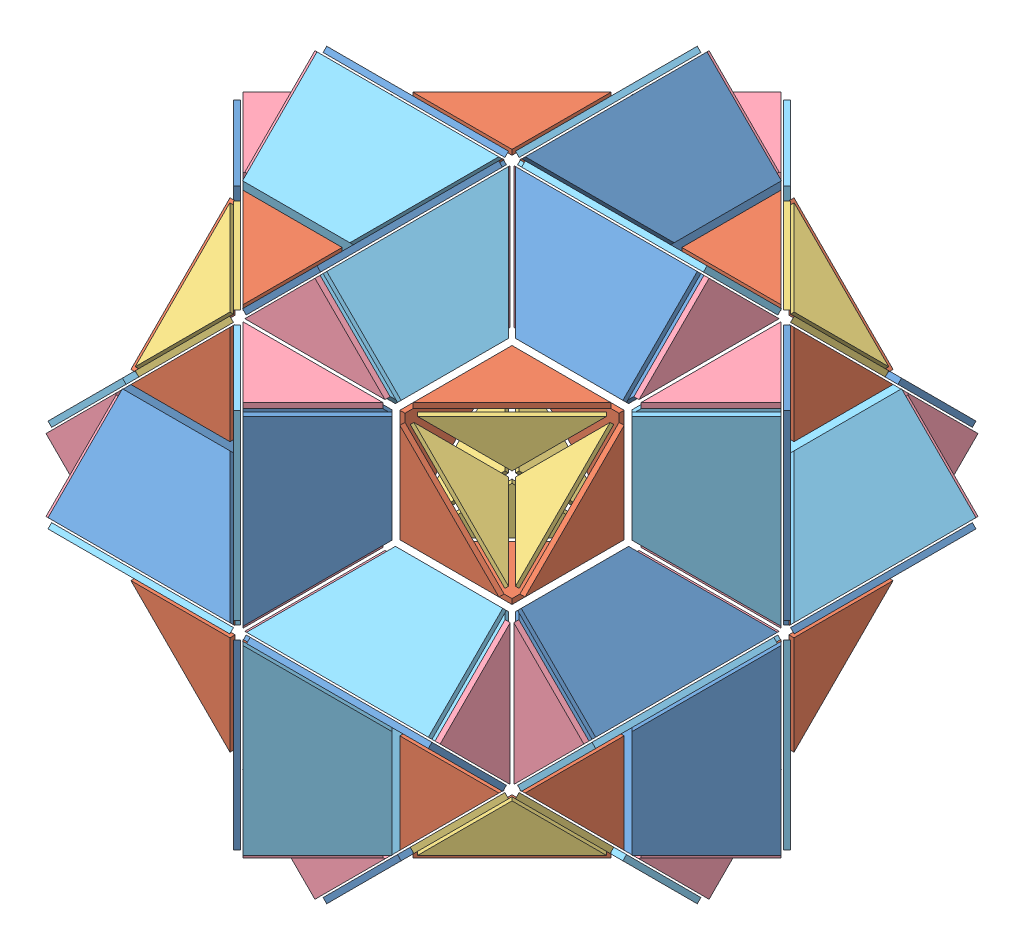
SolidWorks assembly Full Fucker, configuration Default. Lengths in mm.
Overall size (320.14 320.14 320.14).
318 component instances, 12 part files, 6 mates.
Components (placement in the parent):
- Face-1: Face [Default] at origin size (230.41 76.56 230.41)
  - Face Quarter-1: Face Quarter [Default] at origin size (152.13 76.56 114.47)
    - Goux Like-1: Goux Like [Default] at origin (suppressed, hidden)
    - trapezoid-1: trapezoid [Default] at origin size (45.63 45.63 106.26)
    - triangle 1-1: triangle 1 [Default] at origin size (57.93 3 57.93)
    - triangle 2-1: triangle 2 [Default] at origin size (57.43 27.65 57.43)
    - triangle 3-1: triangle 3 [Default] at origin size (81.93 40.97 3)
    - triangle 4-1: triangle 4 [Default] at origin size (106.26 45.63 45.63)
    - Joiner_1-1: Joiner_1 [Default] at (80.4015 -113.7049 80.4015) x (0 -1 0) z (-0.707107 0 0.707107) (suppressed, hidden)
    - Joiner_2-1: Joiner_2 [Default] at (0 -160.803 0) x (-0.707107 -0.707107 0) z (0 0 1) (suppressed, hidden)
    - Joiner_3-1: Joiner_3 [Default] at (80.4015 -80.4015 113.7049) x (0.707107 -0.707107 0) z (-0.707107 -0.707107 0) (suppressed, hidden)
    - Joiner_Open - 1-2: Joiner_Open - 1 [Default] at (0 -113.7049 113.7049) x (0 1 0) z (1 0 0) (suppressed, hidden)
    - Joiner_Open - 2-1: Joiner_Open - 2 [Default] at (47.0981 -113.7049 0) x (-1 0 0) z (0 0 1) (suppressed, hidden)
    - Joiner_Open - 3-1: Joiner_Open - 3 [Default] at (53.601 -107.202 53.601) x (-0.816497 0.408248 0.408248) z (0.57735 0.57735 0.57735) (suppressed, hidden)
  - Face Quarter-2: Face Quarter [Default] x (0 0 -1) z (1 0 0) size (152.13 76.56 114.47)
    - Goux Like-1: Goux Like [Default] at origin (suppressed, hidden)
    - trapezoid-1: trapezoid [Default] at origin size (45.63 45.63 106.26)
    - triangle 1-1: triangle 1 [Default] at origin size (57.93 3 57.93)
    - triangle 2-1: triangle 2 [Default] at origin size (57.43 27.65 57.43)
    - triangle 3-1: triangle 3 [Default] at origin size (81.93 40.97 3)
    - triangle 4-1: triangle 4 [Default] at origin size (106.26 45.63 45.63)
    - Joiner_1-1: Joiner_1 [Default] at (80.4015 -113.7049 80.4015) x (0 -1 0) z (-0.707107 0 0.707107) (suppressed, hidden)
    - Joiner_2-1: Joiner_2 [Default] at (0 -160.803 0) x (-0.707107 -0.707107 0) z (0 0 1) (suppressed, hidden)
    - Joiner_3-1: Joiner_3 [Default] at (80.4015 -80.4015 113.7049) x (0.707107 -0.707107 0) z (-0.707107 -0.707107 0) (suppressed, hidden)
    - Joiner_Open - 1-2: Joiner_Open - 1 [Default] at (0 -113.7049 113.7049) x (0 1 0) z (1 0 0) (suppressed, hidden)
    - Joiner_Open - 2-1: Joiner_Open - 2 [Default] at (47.0981 -113.7049 0) x (-1 0 0) z (0 0 1) (suppressed, hidden)
    - Joiner_Open - 3-1: Joiner_Open - 3 [Default] at (53.601 -107.202 53.601) x (-0.816497 0.408248 0.408248) z (0.57735 0.57735 0.57735) (suppressed, hidden)
  - Face Quarter-3: Face Quarter [Default] x (-1 0 0) z (0 0 -1) size (152.13 76.56 114.47)
    - Goux Like-1: Goux Like [Default] at origin (suppressed, hidden)
    - trapezoid-1: trapezoid [Default] at origin size (45.63 45.63 106.26)
    - triangle 1-1: triangle 1 [Default] at origin size (57.93 3 57.93)
    - triangle 2-1: triangle 2 [Default] at origin size (57.43 27.65 57.43)
    - triangle 3-1: triangle 3 [Default] at origin size (81.93 40.97 3)
    - triangle 4-1: triangle 4 [Default] at origin size (106.26 45.63 45.63)
    - Joiner_1-1: Joiner_1 [Default] at (80.4015 -113.7049 80.4015) x (0 -1 0) z (-0.707107 0 0.707107) (suppressed, hidden)
    - Joiner_2-1: Joiner_2 [Default] at (0 -160.803 0) x (-0.707107 -0.707107 0) z (0 0 1) (suppressed, hidden)
    - Joiner_3-1: Joiner_3 [Default] at (80.4015 -80.4015 113.7049) x (0.707107 -0.707107 0) z (-0.707107 -0.707107 0) (suppressed, hidden)
    - Joiner_Open - 1-2: Joiner_Open - 1 [Default] at (0 -113.7049 113.7049) x (0 1 0) z (1 0 0) (suppressed, hidden)
    - Joiner_Open - 2-1: Joiner_Open - 2 [Default] at (47.0981 -113.7049 0) x (-1 0 0) z (0 0 1) (suppressed, hidden)
    - Joiner_Open - 3-1: Joiner_Open - 3 [Default] at (53.601 -107.202 53.601) x (-0.816497 0.408248 0.408248) z (0.57735 0.57735 0.57735) (suppressed, hidden)
  - Face Quarter-4: Face Quarter [Default] x (0 0 1) z (-1 0 0) size (152.13 76.56 114.47)
    - Goux Like-1: Goux Like [Default] at origin (suppressed, hidden)
    - trapezoid-1: trapezoid [Default] at origin size (45.63 45.63 106.26)
    - triangle 1-1: triangle 1 [Default] at origin size (57.93 3 57.93)
    - triangle 2-1: triangle 2 [Default] at origin size (57.43 27.65 57.43)
    - triangle 3-1: triangle 3 [Default] at origin size (81.93 40.97 3)
    - triangle 4-1: triangle 4 [Default] at origin size (106.26 45.63 45.63)
    - Joiner_1-1: Joiner_1 [Default] at (80.4015 -113.7049 80.4015) x (0 -1 0) z (-0.707107 0 0.707107) (suppressed, hidden)
    - Joiner_2-1: Joiner_2 [Default] at (0 -160.803 0) x (-0.707107 -0.707107 0) z (0 0 1) (suppressed, hidden)
    - Joiner_3-1: Joiner_3 [Default] at (80.4015 -80.4015 113.7049) x (0.707107 -0.707107 0) z (-0.707107 -0.707107 0) (suppressed, hidden)
    - Joiner_Open - 1-2: Joiner_Open - 1 [Default] at (0 -113.7049 113.7049) x (0 1 0) z (1 0 0) (suppressed, hidden)
    - Joiner_Open - 2-1: Joiner_Open - 2 [Default] at (47.0981 -113.7049 0) x (-1 0 0) z (0 0 1) (suppressed, hidden)
    - Joiner_Open - 3-1: Joiner_Open - 3 [Default] at (53.601 -107.202 53.601) x (-0.816497 0.408248 0.408248) z (0.57735 0.57735 0.57735) (suppressed, hidden)
- Face-2: Face [Default] x (1 0 0) z (0 0 -1) size (230.41 76.56 230.41)
  - Face Quarter-1: Face Quarter [Default] at origin size (152.13 76.56 114.47)
    - Goux Like-1: Goux Like [Default] at origin (suppressed, hidden)
    - trapezoid-1: trapezoid [Default] at origin size (45.63 45.63 106.26)
    - triangle 1-1: triangle 1 [Default] at origin size (57.93 3 57.93)
    - triangle 2-1: triangle 2 [Default] at origin size (57.43 27.65 57.43)
    - triangle 3-1: triangle 3 [Default] at origin size (81.93 40.97 3)
    - triangle 4-1: triangle 4 [Default] at origin size (106.26 45.63 45.63)
    - Joiner_1-1: Joiner_1 [Default] at (80.4015 -113.7049 80.4015) x (0 -1 0) z (-0.707107 0 0.707107) (suppressed, hidden)
    - Joiner_2-1: Joiner_2 [Default] at (0 -160.803 0) x (-0.707107 -0.707107 0) z (0 0 1) (suppressed, hidden)
    - Joiner_3-1: Joiner_3 [Default] at (80.4015 -80.4015 113.7049) x (0.707107 -0.707107 0) z (-0.707107 -0.707107 0) (suppressed, hidden)
    - Joiner_Open - 1-2: Joiner_Open - 1 [Default] at (0 -113.7049 113.7049) x (0 1 0) z (1 0 0) (suppressed, hidden)
    - Joiner_Open - 2-1: Joiner_Open - 2 [Default] at (47.0981 -113.7049 0) x (-1 0 0) z (0 0 1) (suppressed, hidden)
    - Joiner_Open - 3-1: Joiner_Open - 3 [Default] at (53.601 -107.202 53.601) x (-0.816497 0.408248 0.408248) z (0.57735 0.57735 0.57735) (suppressed, hidden)
  - Face Quarter-2: Face Quarter [Default] x (0 0 -1) z (1 0 0) size (152.13 76.56 114.47)
    - Goux Like-1: Goux Like [Default] at origin (suppressed, hidden)
    - trapezoid-1: trapezoid [Default] at origin size (45.63 45.63 106.26)
    - triangle 1-1: triangle 1 [Default] at origin size (57.93 3 57.93)
    - triangle 2-1: triangle 2 [Default] at origin size (57.43 27.65 57.43)
    - triangle 3-1: triangle 3 [Default] at origin size (81.93 40.97 3)
    - triangle 4-1: triangle 4 [Default] at origin size (106.26 45.63 45.63)
    - Joiner_1-1: Joiner_1 [Default] at (80.4015 -113.7049 80.4015) x (0 -1 0) z (-0.707107 0 0.707107) (suppressed, hidden)
    - Joiner_2-1: Joiner_2 [Default] at (0 -160.803 0) x (-0.707107 -0.707107 0) z (0 0 1) (suppressed, hidden)
    - Joiner_3-1: Joiner_3 [Default] at (80.4015 -80.4015 113.7049) x (0.707107 -0.707107 0) z (-0.707107 -0.707107 0) (suppressed, hidden)
    - Joiner_Open - 1-2: Joiner_Open - 1 [Default] at (0 -113.7049 113.7049) x (0 1 0) z (1 0 0) (suppressed, hidden)
    - Joiner_Open - 2-1: Joiner_Open - 2 [Default] at (47.0981 -113.7049 0) x (-1 0 0) z (0 0 1) (suppressed, hidden)
    - Joiner_Open - 3-1: Joiner_Open - 3 [Default] at (53.601 -107.202 53.601) x (-0.816497 0.408248 0.408248) z (0.57735 0.57735 0.57735) (suppressed, hidden)
  - Face Quarter-3: Face Quarter [Default] x (-1 0 0) z (0 0 -1) size (152.13 76.56 114.47)
    - Goux Like-1: Goux Like [Default] at origin (suppressed, hidden)
    - trapezoid-1: trapezoid [Default] at origin size (45.63 45.63 106.26)
    - triangle 1-1: triangle 1 [Default] at origin size (57.93 3 57.93)
    - triangle 2-1: triangle 2 [Default] at origin size (57.43 27.65 57.43)
    - triangle 3-1: triangle 3 [Default] at origin size (81.93 40.97 3)
    - triangle 4-1: triangle 4 [Default] at origin size (106.26 45.63 45.63)
    - Joiner_1-1: Joiner_1 [Default] at (80.4015 -113.7049 80.4015) x (0 -1 0) z (-0.707107 0 0.707107) (suppressed, hidden)
    - Joiner_2-1: Joiner_2 [Default] at (0 -160.803 0) x (-0.707107 -0.707107 0) z (0 0 1) (suppressed, hidden)
    - Joiner_3-1: Joiner_3 [Default] at (80.4015 -80.4015 113.7049) x (0.707107 -0.707107 0) z (-0.707107 -0.707107 0) (suppressed, hidden)
    - Joiner_Open - 1-2: Joiner_Open - 1 [Default] at (0 -113.7049 113.7049) x (0 1 0) z (1 0 0) (suppressed, hidden)
    - Joiner_Open - 2-1: Joiner_Open - 2 [Default] at (47.0981 -113.7049 0) x (-1 0 0) z (0 0 1) (suppressed, hidden)
    - Joiner_Open - 3-1: Joiner_Open - 3 [Default] at (53.601 -107.202 53.601) x (-0.816497 0.408248 0.408248) z (0.57735 0.57735 0.57735) (suppressed, hidden)
  - Face Quarter-4: Face Quarter [Default] x (0 0 1) z (-1 0 0) size (152.13 76.56 114.47)
    - Goux Like-1: Goux Like [Default] at origin (suppressed, hidden)
    - trapezoid-1: trapezoid [Default] at origin size (45.63 45.63 106.26)
    - triangle 1-1: triangle 1 [Default] at origin size (57.93 3 57.93)
    - triangle 2-1: triangle 2 [Default] at origin size (57.43 27.65 57.43)
    - triangle 3-1: triangle 3 [Default] at origin size (81.93 40.97 3)
    - triangle 4-1: triangle 4 [Default] at origin size (106.26 45.63 45.63)
    - Joiner_1-1: Joiner_1 [Default] at (80.4015 -113.7049 80.4015) x (0 -1 0) z (-0.707107 0 0.707107) (suppressed, hidden)
    - Joiner_2-1: Joiner_2 [Default] at (0 -160.803 0) x (-0.707107 -0.707107 0) z (0 0 1) (suppressed, hidden)
    - Joiner_3-1: Joiner_3 [Default] at (80.4015 -80.4015 113.7049) x (0.707107 -0.707107 0) z (-0.707107 -0.707107 0) (suppressed, hidden)
    - Joiner_Open - 1-2: Joiner_Open - 1 [Default] at (0 -113.7049 113.7049) x (0 1 0) z (1 0 0) (suppressed, hidden)
    - Joiner_Open - 2-1: Joiner_Open - 2 [Default] at (47.0981 -113.7049 0) x (-1 0 0) z (0 0 1) (suppressed, hidden)
    - Joiner_Open - 3-1: Joiner_Open - 3 [Default] at (53.601 -107.202 53.601) x (-0.816497 0.408248 0.408248) z (0.57735 0.57735 0.57735) (suppressed, hidden)
- Face-3: Face [Default] x (0 1 0) z (0 0 1) size (230.41 76.56 230.41)
  - Face Quarter-1: Face Quarter [Default] at origin size (152.13 76.56 114.47)
    - Goux Like-1: Goux Like [Default] at origin (suppressed, hidden)
    - trapezoid-1: trapezoid [Default] at origin size (45.63 45.63 106.26)
    - triangle 1-1: triangle 1 [Default] at origin size (57.93 3 57.93)
    - triangle 2-1: triangle 2 [Default] at origin size (57.43 27.65 57.43)
    - triangle 3-1: triangle 3 [Default] at origin size (81.93 40.97 3)
    - triangle 4-1: triangle 4 [Default] at origin size (106.26 45.63 45.63)
    - Joiner_1-1: Joiner_1 [Default] at (80.4015 -113.7049 80.4015) x (0 -1 0) z (-0.707107 0 0.707107) (suppressed, hidden)
    - Joiner_2-1: Joiner_2 [Default] at (0 -160.803 0) x (-0.707107 -0.707107 0) z (0 0 1) (suppressed, hidden)
    - Joiner_3-1: Joiner_3 [Default] at (80.4015 -80.4015 113.7049) x (0.707107 -0.707107 0) z (-0.707107 -0.707107 0) (suppressed, hidden)
    - Joiner_Open - 1-2: Joiner_Open - 1 [Default] at (0 -113.7049 113.7049) x (0 1 0) z (1 0 0) (suppressed, hidden)
    - Joiner_Open - 2-1: Joiner_Open - 2 [Default] at (47.0981 -113.7049 0) x (-1 0 0) z (0 0 1) (suppressed, hidden)
    - Joiner_Open - 3-1: Joiner_Open - 3 [Default] at (53.601 -107.202 53.601) x (-0.816497 0.408248 0.408248) z (0.57735 0.57735 0.57735) (suppressed, hidden)
  - Face Quarter-2: Face Quarter [Default] x (0 0 -1) z (1 0 0) size (152.13 76.56 114.47)
    - Goux Like-1: Goux Like [Default] at origin (suppressed, hidden)
    - trapezoid-1: trapezoid [Default] at origin size (45.63 45.63 106.26)
    - triangle 1-1: triangle 1 [Default] at origin size (57.93 3 57.93)
    - triangle 2-1: triangle 2 [Default] at origin size (57.43 27.65 57.43)
    - triangle 3-1: triangle 3 [Default] at origin size (81.93 40.97 3)
    - triangle 4-1: triangle 4 [Default] at origin size (106.26 45.63 45.63)
    - Joiner_1-1: Joiner_1 [Default] at (80.4015 -113.7049 80.4015) x (0 -1 0) z (-0.707107 0 0.707107) (suppressed, hidden)
    - Joiner_2-1: Joiner_2 [Default] at (0 -160.803 0) x (-0.707107 -0.707107 0) z (0 0 1) (suppressed, hidden)
    - Joiner_3-1: Joiner_3 [Default] at (80.4015 -80.4015 113.7049) x (0.707107 -0.707107 0) z (-0.707107 -0.707107 0) (suppressed, hidden)
    - Joiner_Open - 1-2: Joiner_Open - 1 [Default] at (0 -113.7049 113.7049) x (0 1 0) z (1 0 0) (suppressed, hidden)
    - Joiner_Open - 2-1: Joiner_Open - 2 [Default] at (47.0981 -113.7049 0) x (-1 0 0) z (0 0 1) (suppressed, hidden)
    - Joiner_Open - 3-1: Joiner_Open - 3 [Default] at (53.601 -107.202 53.601) x (-0.816497 0.408248 0.408248) z (0.57735 0.57735 0.57735) (suppressed, hidden)
  - Face Quarter-3: Face Quarter [Default] x (-1 0 0) z (0 0 -1) size (152.13 76.56 114.47)
    - Goux Like-1: Goux Like [Default] at origin (suppressed, hidden)
    - trapezoid-1: trapezoid [Default] at origin size (45.63 45.63 106.26)
    - triangle 1-1: triangle 1 [Default] at origin size (57.93 3 57.93)
    - triangle 2-1: triangle 2 [Default] at origin size (57.43 27.65 57.43)
    - triangle 3-1: triangle 3 [Default] at origin size (81.93 40.97 3)
    - triangle 4-1: triangle 4 [Default] at origin size (106.26 45.63 45.63)
    - Joiner_1-1: Joiner_1 [Default] at (80.4015 -113.7049 80.4015) x (0 -1 0) z (-0.707107 0 0.707107) (suppressed, hidden)
    - Joiner_2-1: Joiner_2 [Default] at (0 -160.803 0) x (-0.707107 -0.707107 0) z (0 0 1) (suppressed, hidden)
    - Joiner_3-1: Joiner_3 [Default] at (80.4015 -80.4015 113.7049) x (0.707107 -0.707107 0) z (-0.707107 -0.707107 0) (suppressed, hidden)
    - Joiner_Open - 1-2: Joiner_Open - 1 [Default] at (0 -113.7049 113.7049) x (0 1 0) z (1 0 0) (suppressed, hidden)
    - Joiner_Open - 2-1: Joiner_Open - 2 [Default] at (47.0981 -113.7049 0) x (-1 0 0) z (0 0 1) (suppressed, hidden)
    - Joiner_Open - 3-1: Joiner_Open - 3 [Default] at (53.601 -107.202 53.601) x (-0.816497 0.408248 0.408248) z (0.57735 0.57735 0.57735) (suppressed, hidden)
  - Face Quarter-4: Face Quarter [Default] x (0 0 1) z (-1 0 0) size (152.13 76.56 114.47)
    - Goux Like-1: Goux Like [Default] at origin (suppressed, hidden)
    - trapezoid-1: trapezoid [Default] at origin size (45.63 45.63 106.26)
    - triangle 1-1: triangle 1 [Default] at origin size (57.93 3 57.93)
    - triangle 2-1: triangle 2 [Default] at origin size (57.43 27.65 57.43)
    - triangle 3-1: triangle 3 [Default] at origin size (81.93 40.97 3)
    - triangle 4-1: triangle 4 [Default] at origin size (106.26 45.63 45.63)
    - Joiner_1-1: Joiner_1 [Default] at (80.4015 -113.7049 80.4015) x (0 -1 0) z (-0.707107 0 0.707107) (suppressed, hidden)
    - Joiner_2-1: Joiner_2 [Default] at (0 -160.803 0) x (-0.707107 -0.707107 0) z (0 0 1) (suppressed, hidden)
    - Joiner_3-1: Joiner_3 [Default] at (80.4015 -80.4015 113.7049) x (0.707107 -0.707107 0) z (-0.707107 -0.707107 0) (suppressed, hidden)
    - Joiner_Open - 1-2: Joiner_Open - 1 [Default] at (0 -113.7049 113.7049) x (0 1 0) z (1 0 0) (suppressed, hidden)
    - Joiner_Open - 2-1: Joiner_Open - 2 [Default] at (47.0981 -113.7049 0) x (-1 0 0) z (0 0 1) (suppressed, hidden)
    - Joiner_Open - 3-1: Joiner_Open - 3 [Default] at (53.601 -107.202 53.601) x (-0.816497 0.408248 0.408248) z (0.57735 0.57735 0.57735) (suppressed, hidden)
- Face-4: Face [Default] x (0 1 0) z (1 0 0) size (230.41 76.56 230.41)
  - Face Quarter-1: Face Quarter [Default] at origin size (152.13 76.56 114.47)
    - Goux Like-1: Goux Like [Default] at origin (suppressed, hidden)
    - trapezoid-1: trapezoid [Default] at origin size (45.63 45.63 106.26)
    - triangle 1-1: triangle 1 [Default] at origin size (57.93 3 57.93)
    - triangle 2-1: triangle 2 [Default] at origin size (57.43 27.65 57.43)
    - triangle 3-1: triangle 3 [Default] at origin size (81.93 40.97 3)
    - triangle 4-1: triangle 4 [Default] at origin size (106.26 45.63 45.63)
    - Joiner_1-1: Joiner_1 [Default] at (80.4015 -113.7049 80.4015) x (0 -1 0) z (-0.707107 0 0.707107) (suppressed, hidden)
    - Joiner_2-1: Joiner_2 [Default] at (0 -160.803 0) x (-0.707107 -0.707107 0) z (0 0 1) (suppressed, hidden)
    - Joiner_3-1: Joiner_3 [Default] at (80.4015 -80.4015 113.7049) x (0.707107 -0.707107 0) z (-0.707107 -0.707107 0) (suppressed, hidden)
    - Joiner_Open - 1-2: Joiner_Open - 1 [Default] at (0 -113.7049 113.7049) x (0 1 0) z (1 0 0) (suppressed, hidden)
    - Joiner_Open - 2-1: Joiner_Open - 2 [Default] at (47.0981 -113.7049 0) x (-1 0 0) z (0 0 1) (suppressed, hidden)
    - Joiner_Open - 3-1: Joiner_Open - 3 [Default] at (53.601 -107.202 53.601) x (-0.816497 0.408248 0.408248) z (0.57735 0.57735 0.57735) (suppressed, hidden)
  - Face Quarter-2: Face Quarter [Default] x (0 0 -1) z (1 0 0) size (152.13 76.56 114.47)
    - Goux Like-1: Goux Like [Default] at origin (suppressed, hidden)
    - trapezoid-1: trapezoid [Default] at origin size (45.63 45.63 106.26)
    - triangle 1-1: triangle 1 [Default] at origin size (57.93 3 57.93)
    - triangle 2-1: triangle 2 [Default] at origin size (57.43 27.65 57.43)
    - triangle 3-1: triangle 3 [Default] at origin size (81.93 40.97 3)
    - triangle 4-1: triangle 4 [Default] at origin size (106.26 45.63 45.63)
    - Joiner_1-1: Joiner_1 [Default] at (80.4015 -113.7049 80.4015) x (0 -1 0) z (-0.707107 0 0.707107) (suppressed, hidden)
    - Joiner_2-1: Joiner_2 [Default] at (0 -160.803 0) x (-0.707107 -0.707107 0) z (0 0 1) (suppressed, hidden)
    - Joiner_3-1: Joiner_3 [Default] at (80.4015 -80.4015 113.7049) x (0.707107 -0.707107 0) z (-0.707107 -0.707107 0) (suppressed, hidden)
    - Joiner_Open - 1-2: Joiner_Open - 1 [Default] at (0 -113.7049 113.7049) x (0 1 0) z (1 0 0) (suppressed, hidden)
    - Joiner_Open - 2-1: Joiner_Open - 2 [Default] at (47.0981 -113.7049 0) x (-1 0 0) z (0 0 1) (suppressed, hidden)
    - Joiner_Open - 3-1: Joiner_Open - 3 [Default] at (53.601 -107.202 53.601) x (-0.816497 0.408248 0.408248) z (0.57735 0.57735 0.57735) (suppressed, hidden)
  - Face Quarter-3: Face Quarter [Default] x (-1 0 0) z (0 0 -1) size (152.13 76.56 114.47)
    - Goux Like-1: Goux Like [Default] at origin (suppressed, hidden)
    - trapezoid-1: trapezoid [Default] at origin size (45.63 45.63 106.26)
    - triangle 1-1: triangle 1 [Default] at origin size (57.93 3 57.93)
    - triangle 2-1: triangle 2 [Default] at origin size (57.43 27.65 57.43)
    - triangle 3-1: triangle 3 [Default] at origin size (81.93 40.97 3)
    - triangle 4-1: triangle 4 [Default] at origin size (106.26 45.63 45.63)
    - Joiner_1-1: Joiner_1 [Default] at (80.4015 -113.7049 80.4015) x (0 -1 0) z (-0.707107 0 0.707107) (suppressed, hidden)
    - Joiner_2-1: Joiner_2 [Default] at (0 -160.803 0) x (-0.707107 -0.707107 0) z (0 0 1) (suppressed, hidden)
    - Joiner_3-1: Joiner_3 [Default] at (80.4015 -80.4015 113.7049) x (0.707107 -0.707107 0) z (-0.707107 -0.707107 0) (suppressed, hidden)
    - Joiner_Open - 1-2: Joiner_Open - 1 [Default] at (0 -113.7049 113.7049) x (0 1 0) z (1 0 0) (suppressed, hidden)
    - Joiner_Open - 2-1: Joiner_Open - 2 [Default] at (47.0981 -113.7049 0) x (-1 0 0) z (0 0 1) (suppressed, hidden)
    - Joiner_Open - 3-1: Joiner_Open - 3 [Default] at (53.601 -107.202 53.601) x (-0.816497 0.408248 0.408248) z (0.57735 0.57735 0.57735) (suppressed, hidden)
  - Face Quarter-4: Face Quarter [Default] x (0 0 1) z (-1 0 0) size (152.13 76.56 114.47)
    - Goux Like-1: Goux Like [Default] at origin (suppressed, hidden)
    - trapezoid-1: trapezoid [Default] at origin size (45.63 45.63 106.26)
    - triangle 1-1: triangle 1 [Default] at origin size (57.93 3 57.93)
    - triangle 2-1: triangle 2 [Default] at origin size (57.43 27.65 57.43)
    - triangle 3-1: triangle 3 [Default] at origin size (81.93 40.97 3)
    - triangle 4-1: triangle 4 [Default] at origin size (106.26 45.63 45.63)
    - Joiner_1-1: Joiner_1 [Default] at (80.4015 -113.7049 80.4015) x (0 -1 0) z (-0.707107 0 0.707107) (suppressed, hidden)
    - Joiner_2-1: Joiner_2 [Default] at (0 -160.803 0) x (-0.707107 -0.707107 0) z (0 0 1) (suppressed, hidden)
    - Joiner_3-1: Joiner_3 [Default] at (80.4015 -80.4015 113.7049) x (0.707107 -0.707107 0) z (-0.707107 -0.707107 0) (suppressed, hidden)
    - Joiner_Open - 1-2: Joiner_Open - 1 [Default] at (0 -113.7049 113.7049) x (0 1 0) z (1 0 0) (suppressed, hidden)
    - Joiner_Open - 2-1: Joiner_Open - 2 [Default] at (47.0981 -113.7049 0) x (-1 0 0) z (0 0 1) (suppressed, hidden)
    - Joiner_Open - 3-1: Joiner_Open - 3 [Default] at (53.601 -107.202 53.601) x (-0.816497 0.408248 0.408248) z (0.57735 0.57735 0.57735) (suppressed, hidden)
- Face-5: Face [Default] x (0 1 0) z (0 0 -1) size (230.41 76.56 230.41)
  - Face Quarter-1: Face Quarter [Default] at origin size (152.13 76.56 114.47)
    - Goux Like-1: Goux Like [Default] at origin (suppressed, hidden)
    - trapezoid-1: trapezoid [Default] at origin size (45.63 45.63 106.26)
    - triangle 1-1: triangle 1 [Default] at origin size (57.93 3 57.93)
    - triangle 2-1: triangle 2 [Default] at origin size (57.43 27.65 57.43)
    - triangle 3-1: triangle 3 [Default] at origin size (81.93 40.97 3)
    - triangle 4-1: triangle 4 [Default] at origin size (106.26 45.63 45.63)
    - Joiner_1-1: Joiner_1 [Default] at (80.4015 -113.7049 80.4015) x (0 -1 0) z (-0.707107 0 0.707107) (suppressed, hidden)
    - Joiner_2-1: Joiner_2 [Default] at (0 -160.803 0) x (-0.707107 -0.707107 0) z (0 0 1) (suppressed, hidden)
    - Joiner_3-1: Joiner_3 [Default] at (80.4015 -80.4015 113.7049) x (0.707107 -0.707107 0) z (-0.707107 -0.707107 0) (suppressed, hidden)
    - Joiner_Open - 1-2: Joiner_Open - 1 [Default] at (0 -113.7049 113.7049) x (0 1 0) z (1 0 0) (suppressed, hidden)
    - Joiner_Open - 2-1: Joiner_Open - 2 [Default] at (47.0981 -113.7049 0) x (-1 0 0) z (0 0 1) (suppressed, hidden)
    - Joiner_Open - 3-1: Joiner_Open - 3 [Default] at (53.601 -107.202 53.601) x (-0.816497 0.408248 0.408248) z (0.57735 0.57735 0.57735) (suppressed, hidden)
  - Face Quarter-2: Face Quarter [Default] x (0 0 -1) z (1 0 0) size (152.13 76.56 114.47)
    - Goux Like-1: Goux Like [Default] at origin (suppressed, hidden)
    - trapezoid-1: trapezoid [Default] at origin size (45.63 45.63 106.26)
    - triangle 1-1: triangle 1 [Default] at origin size (57.93 3 57.93)
    - triangle 2-1: triangle 2 [Default] at origin size (57.43 27.65 57.43)
    - triangle 3-1: triangle 3 [Default] at origin size (81.93 40.97 3)
    - triangle 4-1: triangle 4 [Default] at origin size (106.26 45.63 45.63)
    - Joiner_1-1: Joiner_1 [Default] at (80.4015 -113.7049 80.4015) x (0 -1 0) z (-0.707107 0 0.707107) (suppressed, hidden)
    - Joiner_2-1: Joiner_2 [Default] at (0 -160.803 0) x (-0.707107 -0.707107 0) z (0 0 1) (suppressed, hidden)
    - Joiner_3-1: Joiner_3 [Default] at (80.4015 -80.4015 113.7049) x (0.707107 -0.707107 0) z (-0.707107 -0.707107 0) (suppressed, hidden)
    - Joiner_Open - 1-2: Joiner_Open - 1 [Default] at (0 -113.7049 113.7049) x (0 1 0) z (1 0 0) (suppressed, hidden)
    - Joiner_Open - 2-1: Joiner_Open - 2 [Default] at (47.0981 -113.7049 0) x (-1 0 0) z (0 0 1) (suppressed, hidden)
    - Joiner_Open - 3-1: Joiner_Open - 3 [Default] at (53.601 -107.202 53.601) x (-0.816497 0.408248 0.408248) z (0.57735 0.57735 0.57735) (suppressed, hidden)
  - Face Quarter-3: Face Quarter [Default] x (-1 0 0) z (0 0 -1) size (152.13 76.56 114.47)
    - Goux Like-1: Goux Like [Default] at origin (suppressed, hidden)
    - trapezoid-1: trapezoid [Default] at origin size (45.63 45.63 106.26)
    - triangle 1-1: triangle 1 [Default] at origin size (57.93 3 57.93)
    - triangle 2-1: triangle 2 [Default] at origin size (57.43 27.65 57.43)
    - triangle 3-1: triangle 3 [Default] at origin size (81.93 40.97 3)
    - triangle 4-1: triangle 4 [Default] at origin size (106.26 45.63 45.63)
    - Joiner_1-1: Joiner_1 [Default] at (80.4015 -113.7049 80.4015) x (0 -1 0) z (-0.707107 0 0.707107) (suppressed, hidden)
    - Joiner_2-1: Joiner_2 [Default] at (0 -160.803 0) x (-0.707107 -0.707107 0) z (0 0 1) (suppressed, hidden)
    - Joiner_3-1: Joiner_3 [Default] at (80.4015 -80.4015 113.7049) x (0.707107 -0.707107 0) z (-0.707107 -0.707107 0) (suppressed, hidden)
    - Joiner_Open - 1-2: Joiner_Open - 1 [Default] at (0 -113.7049 113.7049) x (0 1 0) z (1 0 0) (suppressed, hidden)
    - Joiner_Open - 2-1: Joiner_Open - 2 [Default] at (47.0981 -113.7049 0) x (-1 0 0) z (0 0 1) (suppressed, hidden)
    - Joiner_Open - 3-1: Joiner_Open - 3 [Default] at (53.601 -107.202 53.601) x (-0.816497 0.408248 0.408248) z (0.57735 0.57735 0.57735) (suppressed, hidden)
  - Face Quarter-4: Face Quarter [Default] x (0 0 1) z (-1 0 0) size (152.13 76.56 114.47)
    - Goux Like-1: Goux Like [Default] at origin (suppressed, hidden)
    - trapezoid-1: trapezoid [Default] at origin size (45.63 45.63 106.26)
    - triangle 1-1: triangle 1 [Default] at origin size (57.93 3 57.93)
    - triangle 2-1: triangle 2 [Default] at origin size (57.43 27.65 57.43)
    - triangle 3-1: triangle 3 [Default] at origin size (81.93 40.97 3)
    - triangle 4-1: triangle 4 [Default] at origin size (106.26 45.63 45.63)
    - Joiner_1-1: Joiner_1 [Default] at (80.4015 -113.7049 80.4015) x (0 -1 0) z (-0.707107 0 0.707107) (suppressed, hidden)
    - Joiner_2-1: Joiner_2 [Default] at (0 -160.803 0) x (-0.707107 -0.707107 0) z (0 0 1) (suppressed, hidden)
    - Joiner_3-1: Joiner_3 [Default] at (80.4015 -80.4015 113.7049) x (0.707107 -0.707107 0) z (-0.707107 -0.707107 0) (suppressed, hidden)
    - Joiner_Open - 1-2: Joiner_Open - 1 [Default] at (0 -113.7049 113.7049) x (0 1 0) z (1 0 0) (suppressed, hidden)
    - Joiner_Open - 2-1: Joiner_Open - 2 [Default] at (47.0981 -113.7049 0) x (-1 0 0) z (0 0 1) (suppressed, hidden)
    - Joiner_Open - 3-1: Joiner_Open - 3 [Default] at (53.601 -107.202 53.601) x (-0.816497 0.408248 0.408248) z (0.57735 0.57735 0.57735) (suppressed, hidden)
- Face-6: Face [Default] x (0 1 0) z (-1 0 0) size (230.41 76.56 230.41)
  - Face Quarter-1: Face Quarter [Default] at origin size (152.13 76.56 114.47)
    - Goux Like-1: Goux Like [Default] at origin (suppressed, hidden)
    - trapezoid-1: trapezoid [Default] at origin size (45.63 45.63 106.26)
    - triangle 1-1: triangle 1 [Default] at origin size (57.93 3 57.93)
    - triangle 2-1: triangle 2 [Default] at origin size (57.43 27.65 57.43)
    - triangle 3-1: triangle 3 [Default] at origin size (81.93 40.97 3)
    - triangle 4-1: triangle 4 [Default] at origin size (106.26 45.63 45.63)
    - Joiner_1-1: Joiner_1 [Default] at (80.4015 -113.7049 80.4015) x (0 -1 0) z (-0.707107 0 0.707107) (suppressed, hidden)
    - Joiner_2-1: Joiner_2 [Default] at (0 -160.803 0) x (-0.707107 -0.707107 0) z (0 0 1) (suppressed, hidden)
    - Joiner_3-1: Joiner_3 [Default] at (80.4015 -80.4015 113.7049) x (0.707107 -0.707107 0) z (-0.707107 -0.707107 0) (suppressed, hidden)
    - Joiner_Open - 1-2: Joiner_Open - 1 [Default] at (0 -113.7049 113.7049) x (0 1 0) z (1 0 0) (suppressed, hidden)
    - Joiner_Open - 2-1: Joiner_Open - 2 [Default] at (47.0981 -113.7049 0) x (-1 0 0) z (0 0 1) (suppressed, hidden)
    - Joiner_Open - 3-1: Joiner_Open - 3 [Default] at (53.601 -107.202 53.601) x (-0.816497 0.408248 0.408248) z (0.57735 0.57735 0.57735) (suppressed, hidden)
  - Face Quarter-2: Face Quarter [Default] x (0 0 -1) z (1 0 0) size (152.13 76.56 114.47)
    - Goux Like-1: Goux Like [Default] at origin (suppressed, hidden)
    - trapezoid-1: trapezoid [Default] at origin size (45.63 45.63 106.26)
    - triangle 1-1: triangle 1 [Default] at origin size (57.93 3 57.93)
    - triangle 2-1: triangle 2 [Default] at origin size (57.43 27.65 57.43)
    - triangle 3-1: triangle 3 [Default] at origin size (81.93 40.97 3)
    - triangle 4-1: triangle 4 [Default] at origin size (106.26 45.63 45.63)
    - Joiner_1-1: Joiner_1 [Default] at (80.4015 -113.7049 80.4015) x (0 -1 0) z (-0.707107 0 0.707107) (suppressed, hidden)
    - Joiner_2-1: Joiner_2 [Default] at (0 -160.803 0) x (-0.707107 -0.707107 0) z (0 0 1) (suppressed, hidden)
    - Joiner_3-1: Joiner_3 [Default] at (80.4015 -80.4015 113.7049) x (0.707107 -0.707107 0) z (-0.707107 -0.707107 0) (suppressed, hidden)
    - Joiner_Open - 1-2: Joiner_Open - 1 [Default] at (0 -113.7049 113.7049) x (0 1 0) z (1 0 0) (suppressed, hidden)
    - Joiner_Open - 2-1: Joiner_Open - 2 [Default] at (47.0981 -113.7049 0) x (-1 0 0) z (0 0 1) (suppressed, hidden)
    - Joiner_Open - 3-1: Joiner_Open - 3 [Default] at (53.601 -107.202 53.601) x (-0.816497 0.408248 0.408248) z (0.57735 0.57735 0.57735) (suppressed, hidden)
  - Face Quarter-3: Face Quarter [Default] x (-1 0 0) z (0 0 -1) size (152.13 76.56 114.47)
    - Goux Like-1: Goux Like [Default] at origin (suppressed, hidden)
    - trapezoid-1: trapezoid [Default] at origin size (45.63 45.63 106.26)
    - triangle 1-1: triangle 1 [Default] at origin size (57.93 3 57.93)
    - triangle 2-1: triangle 2 [Default] at origin size (57.43 27.65 57.43)
    - triangle 3-1: triangle 3 [Default] at origin size (81.93 40.97 3)
    - triangle 4-1: triangle 4 [Default] at origin size (106.26 45.63 45.63)
    - Joiner_1-1: Joiner_1 [Default] at (80.4015 -113.7049 80.4015) x (0 -1 0) z (-0.707107 0 0.707107) (suppressed, hidden)
    - Joiner_2-1: Joiner_2 [Default] at (0 -160.803 0) x (-0.707107 -0.707107 0) z (0 0 1) (suppressed, hidden)
    - Joiner_3-1: Joiner_3 [Default] at (80.4015 -80.4015 113.7049) x (0.707107 -0.707107 0) z (-0.707107 -0.707107 0) (suppressed, hidden)
    - Joiner_Open - 1-2: Joiner_Open - 1 [Default] at (0 -113.7049 113.7049) x (0 1 0) z (1 0 0) (suppressed, hidden)
    - Joiner_Open - 2-1: Joiner_Open - 2 [Default] at (47.0981 -113.7049 0) x (-1 0 0) z (0 0 1) (suppressed, hidden)
    - Joiner_Open - 3-1: Joiner_Open - 3 [Default] at (53.601 -107.202 53.601) x (-0.816497 0.408248 0.408248) z (0.57735 0.57735 0.57735) (suppressed, hidden)
  - Face Quarter-4: Face Quarter [Default] x (0 0 1) z (-1 0 0) size (152.13 76.56 114.47)
    - Goux Like-1: Goux Like [Default] at origin (suppressed, hidden)
    - trapezoid-1: trapezoid [Default] at origin size (45.63 45.63 106.26)
    - triangle 1-1: triangle 1 [Default] at origin size (57.93 3 57.93)
    - triangle 2-1: triangle 2 [Default] at origin size (57.43 27.65 57.43)
    - triangle 3-1: triangle 3 [Default] at origin size (81.93 40.97 3)
    - triangle 4-1: triangle 4 [Default] at origin size (106.26 45.63 45.63)
    - Joiner_1-1: Joiner_1 [Default] at (80.4015 -113.7049 80.4015) x (0 -1 0) z (-0.707107 0 0.707107) (suppressed, hidden)
    - Joiner_2-1: Joiner_2 [Default] at (0 -160.803 0) x (-0.707107 -0.707107 0) z (0 0 1) (suppressed, hidden)
    - Joiner_3-1: Joiner_3 [Default] at (80.4015 -80.4015 113.7049) x (0.707107 -0.707107 0) z (-0.707107 -0.707107 0) (suppressed, hidden)
    - Joiner_Open - 1-2: Joiner_Open - 1 [Default] at (0 -113.7049 113.7049) x (0 1 0) z (1 0 0) (suppressed, hidden)
    - Joiner_Open - 2-1: Joiner_Open - 2 [Default] at (47.0981 -113.7049 0) x (-1 0 0) z (0 0 1) (suppressed, hidden)
    - Joiner_Open - 3-1: Joiner_Open - 3 [Default] at (53.601 -107.202 53.601) x (-0.816497 0.408248 0.408248) z (0.57735 0.57735 0.57735) (suppressed, hidden)
Mates (geometry in assembly coordinates):
- Coincident1: coincident aligned: plane of Face-2 through (0 0 0) normal (1 0 0)
- Coincident2: coincident anti-aligned: plane of Face-2 through (0 0 0) normal (0 -1 0)
- Coincident3: coincident anti-aligned: plane of Face-2 through (0 0 0) normal (0 0 -1)
- Coincident5: coincident: point of Face-3
- Coincident6: coincident anti-aligned: plane of Face-3 through (0 0 0) normal (-1 0 0)
- Coincident7: coincident aligned: plane of Face-3/Face Quarter-2 through (0 0 0) normal (0 1 0)
